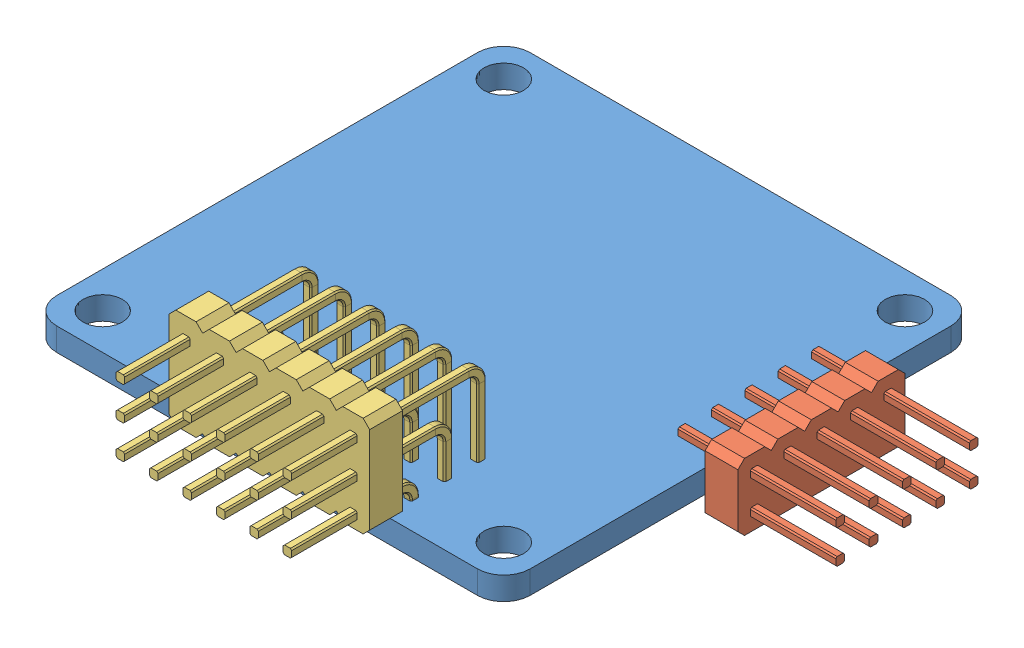
SolidWorks assembly Distrubution Board Assembly, configuration Default. Lengths in mm.
Overall size (45 11.52 43.18).
3 component instances, 3 part files, 6 mates.
Components (placement in the parent):
- Drone Distrubution Board Component 3-5: Drone Distrubution Board Component 3 [Default] at (5.1894 7.6198 -36.7276) x (1 0 0) z (0 0 -1) size (36 3.75 36)
- Electrical Unit Component 12-2: Electrical Unit Component 12 [Default] at (20.1894 5.4367 -35.2976) x (0 -1 0) z (0 0 1) size (5.08 12 12.7)
- Component Electrical Unit 2 -13-2: Component Electrical Unit 2 -13 [Default] at (1.2194 4.7148 -26.0276) x (0 0 1) z (-1 0 0) size (14.8 10.68 15.24)
Mates (geometry in assembly coordinates):
- Coincident1: coincident: Drone Distrubution Board Component 3-5, Electrical Unit Component 12-2
- Parallel2: parallel: Drone Distrubution Board Component 3-5, Component Electrical Unit 2 -13-2
- Parallel3: parallel: Drone Distrubution Board Component 3-5, Component Electrical Unit 2 -13-2
- Distance3: distance: Drone Distrubution Board Component 3-5, Component Electrical Unit 2 -13-2
- Distance4: distance: Drone Distrubution Board Component 3-5, Component Electrical Unit 2 -13-2
- Distance5: distance: Component Electrical Unit 2 -13-2, Drone Distrubution Board Component 3-5
